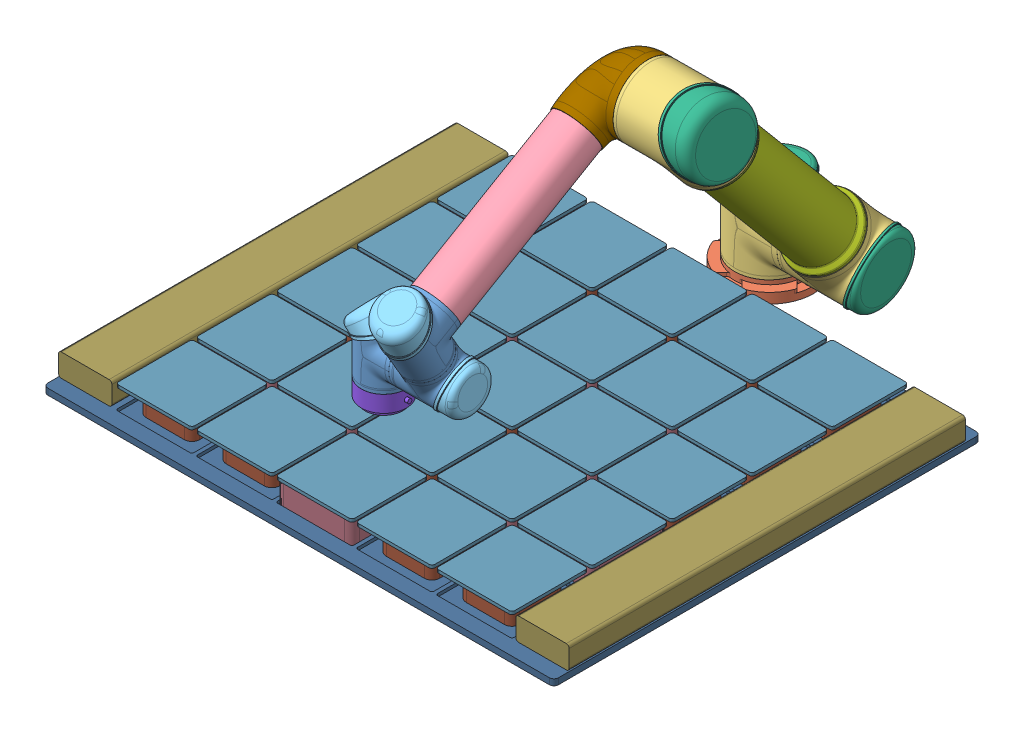
SolidWorks assembly EE206 Project, configuration Default. Lengths in mm.
Overall size (850.9 499.9 869.58).
71 component instances, 14 part files, 18 mates.
Components (placement in the parent):
- UR5-1: UR5 [Default] at origin size (344.78 499.9 760.49)
  - Size 1_House_r13_Simple-1: Size 1_House_r13_Simple [Default] at (17.3569 137.7558 566.8462) x (-0.000585 0.866025 0.500001) z (-0.003317 0.499996 -0.866021) size (83 87.5 79.44)
  - Size 1_House_r13_Simple-2: Size 1_House_r13_Simple [Default] at (-75.6425 137.5544 567.0862) x (0.999994 0.002165 -0.002581) z (0.002581 0.000003 0.999997) size (83 87.5 79.44)
  - Size 3_Round base_r02_Simple-1: Size 3_Round base_r02_Simple [Default] at (0 3 0) x (0 -1 0) z (0 0 -1) size (24 154.92 154.92)
  - Size 3_House_r11_Simple-1: Size 3_House_r11_Simple [Default] at (135.7 414.7689 273.1847) x (-0.999994 -0.002165 0.002581) z (-0.003369 0.642784 -0.76604) size (129.79 128.5 124.27)
  - Size 1 r¬r_r01_Simple-1: Size 1 r¬r_r01_Simple [Default] at (16.6562 315.7154 444.6107) x (-0.999994 -0.002165 0.002581) z (0.003317 -0.499996 0.866021) size (75 75 272.93)
  - Size 1_Joint lid_r07_Simple-1: Size 1_Joint lid_r07_Simple [Default] at (17.3025 218.2961 613.3463) x (-0.003317 0.499996 -0.866021) z (0.999994 0.002165 -0.002581) size (77.51 51.3 77.52)
  - Size 3_Joint lid_r06_Simple-1: Size 3_Joint lid_r06_Simple [Default] at (135.7003 89.2 0) x (-1 0 0) z (0 -0.642788 0.766044) size (62.7 119 119.01)
  - Size 1_House_r13_Simple-3: Size 1_House_r13_Simple [Default] at (17.3025 218.2961 613.3463) x (-0.003317 0.499996 -0.866021) z (0.999994 0.002165 -0.002581) size (83 87.5 79.44)
  - Size 3_House_r11_Simple-2: Size 3_House_r11_Simple [Default] at (135.7 89.2 0) x (-1 0 0) z (0 -0.642788 0.766044) size (129.79 128.5 124.27)
  - Size 3_Over arm_r01_Simpel-1: Size 3_Over arm_r01_Simpel [Default] at (135.7 251.9844 136.5924) x (0 -0.766044 -0.642788) z (-0.756553 0.42034 -0.500941) size (284 114.3 114.3)
  - Size 3_House_r11_Simple-3: Size 3_House_r11_Simple [Default] at (0 89.2 0) x (0 -1 0) z (0 0 -1) size (129.79 128.5 124.27)
  - Size 1_Joint lid_r07_Simple-2: Size 1_Joint lid_r07_Simple [Default] at (-59.9925 144.481 567.0458) x (-0.674003 -0.738727 0.001741) z (-0.002581 -0.000003 -0.999997) size (77.51 51.3 77.52)
  - Size 3_Joint lid_r06_Simple-2: Size 3_Joint lid_r06_Simple [Default] at (135.0062 415.9165 274.1507) x (-0.999994 -0.002165 0.002581) z (-0.003369 0.642784 -0.76604) size (62.7 119 119.01)
  - Size 1_Tool flange_r03_Simple-1: Size 1_Tool flange_r03_Simple [Default] at (-75.5397 90.0545 567.0861) x (0.002165 -0.999998 -0.000003) z (0.002581 0.000003 0.999997) size (34.5 80.5 75)
  - Size 1_Joint lid_r07_Simple-3: Size 1_Joint lid_r07_Simple [Default] at (17.3569 137.7558 566.8462) x (-0.000585 0.866025 0.500001) z (-0.003317 0.499996 -0.866021) size (77.51 51.3 77.52)
  - Size 3 to Size 1_Angle_r02_Simple-1: Size 3 to Size 1_Angle_r02_Simple [Default] at (16.0007 414.5097 273.4936) x (-0.003317 0.499996 -0.866021) z (-0.000585 0.866025 0.500001) size (132.01 97.09 116.02)
  - Size 3_Joint lid_r06_Simple-3: Size 3_Joint lid_r06_Simple [Default] at (-1.5 88.5062 0) x (0 -1 0) z (0 0 -1) size (62.7 119 119.01)
- Grid Frame-2: Grid Frame [Default] at (0 5.08 429.1) x (0 0 1) z (-1 0 0) size (711.2 10.16 850.9)
- Block Foam-1: Block Foam [Default] at (266.7 5.08 162.4) x (0 0 1) z (-1 0 0) size (88.9 38.1 88.9)
- End Block-1: End Block [Default] at (-381 10.16 429.1) x (0 0 1) z (-1 0 0) size (660.4 38.1 88.9)
- Block Wood-1: Block Wood [Default] at (-266.7 5.08 162.4) x (0 0 1) z (-1 0 0) size (127 38.1 127)
- Block Foam-2: Block Foam [Default] at (266.7 5.08 295.75) x (0 0 1) z (-1 0 0) size (88.9 38.1 88.9)
- Block Foam-3: Block Foam [Default] at (266.7 5.08 429.1) x (0 0 1) z (-1 0 0) size (88.9 38.1 88.9)
- Block Foam-5: Block Foam [Default] at (266.7 5.08 695.8) x (0 0 1) z (-1 0 0) size (88.9 38.1 88.9)
- Block Foam-6: Block Foam [Default] at (133.35 5.08 162.4) x (0 0 1) z (-1 0 0) size (88.9 38.1 88.9)
- Block Foam-10: Block Foam [Default] at (133.35 5.08 695.8) x (0 0 1) z (-1 0 0) size (88.9 38.1 88.9)
- Block Foam-11: Block Foam [Default] at (0 5.08 162.4) x (0 0 1) z (-1 0 0) size (88.9 38.1 88.9)
- Block Foam-13: Block Foam [Default] at (0 5.08 429.1) x (0 0 1) z (-1 0 0) size (88.9 38.1 88.9)
- Block Foam-14: Block Foam [Default] at (0 5.08 562.45) x (0 0 1) z (-1 0 0) size (88.9 38.1 88.9)
- Block Foam-16: Block Foam [Default] at (-133.35 5.08 162.4) x (0 0 1) z (-1 0 0) size (88.9 38.1 88.9)
- Block Foam-18: Block Foam [Default] at (-133.35 5.08 429.1) x (0 0 1) z (-1 0 0) size (88.9 38.1 88.9)
- Block Foam-20: Block Foam [Default] at (-133.35 5.08 695.8) x (0 0 1) z (-1 0 0) size (88.9 38.1 88.9)
- Block Foam-23: Block Foam [Default] at (-266.7 5.08 429.1) x (0 0 1) z (-1 0 0) size (88.9 38.1 88.9)
- Block Foam-25: Block Foam [Default] at (-266.7 5.08 695.8) x (0 0 1) z (-1 0 0) size (88.9 38.1 88.9)
- Block Wood-2: Block Wood [Default] at (-266.7 5.08 295.75) x (0 0 1) z (-1 0 0) size (127 38.1 127)
- Block Wood-3: Block Wood [Default] at (-266.7 5.08 562.45) x (0 0 1) z (-1 0 0) size (127 38.1 127)
- Block Wood-4: Block Wood [Default] at (-133.35 5.08 295.75) x (0 0 1) z (-1 0 0) size (127 38.1 127)
- Block Wood-5: Block Wood [Default] at (-133.35 5.08 562.45) x (0 0 1) z (-1 0 0) size (127 38.1 127)
- Block Wood-6: Block Wood [Default] at (0 5.08 295.75) x (0 0 1) z (-1 0 0) size (127 38.1 127)
- Block Wood-7: Block Wood [Default] at (0 5.08 695.8) x (0 0 1) z (-1 0 0) size (127 38.1 127)
- Block Wood-8: Block Wood [Default] at (133.35 5.08 295.75) x (0 0 1) z (-1 0 0) size (127 38.1 127)
- Block Wood-9: Block Wood [Default] at (133.35 5.08 429.1) x (0 0 1) z (-1 0 0) size (127 38.1 127)
- Block Wood-10: Block Wood [Default] at (133.35 5.08 562.45) x (0 0 1) z (-1 0 0) size (127 38.1 127)
- Block Wood-11: Block Wood [Default] at (266.7 5.08 562.45) x (0 0 1) z (-1 0 0) size (127 38.1 127)
- Tile-1: Tile [Default] at (266.7 43.18 162.4) x (0 0 1) z (-1 0 0) size (127 5.08 127)
- Tile-2: Tile [Default] at (266.7 43.18 295.75) x (0 0 1) z (-1 0 0) size (127 5.08 127)
- Tile-3: Tile [Default] at (266.7 43.18 429.1) x (0 0 1) z (-1 0 0) size (127 5.08 127)
- Tile-4: Tile [Default] at (266.7 43.18 562.45) x (0 0 1) z (-1 0 0) size (127 5.08 127)
- Tile-5: Tile [Default] at (266.7 43.18 695.8) x (0 0 1) z (-1 0 0) size (127 5.08 127)
- Tile-6: Tile [Default] at (133.35 43.18 162.4) x (0 0 1) z (-1 0 0) size (127 5.08 127)
- Tile-7: Tile [Default] at (133.35 43.18 295.75) x (0 0 1) z (-1 0 0) size (127 5.08 127)
- Tile-8: Tile [Default] at (133.35 43.18 429.1) x (0 0 1) z (-1 0 0) size (127 5.08 127)
- Tile-9: Tile [Default] at (133.35 43.18 562.45) x (0 0 1) z (-1 0 0) size (127 5.08 127)
- Tile-10: Tile [Default] at (133.35 43.18 695.8) x (0 0 1) z (-1 0 0) size (127 5.08 127)
- Tile-11: Tile [Default] at (0 43.18 162.4) x (0 0 1) z (-1 0 0) size (127 5.08 127)
- Tile-12: Tile [Default] at (0 43.18 295.75) x (0 0 1) z (-1 0 0) size (127 5.08 127)
- Tile-13: Tile [Default] at (0 43.18 429.1) x (0 0 1) z (-1 0 0) size (127 5.08 127)
- Tile-14: Tile [Default] at (0 43.18 562.45) x (0 0 1) z (-1 0 0) size (127 5.08 127)
- Tile-15: Tile [Default] at (0 43.18 695.8) x (0 0 1) z (-1 0 0) size (127 5.08 127)
- Tile-16: Tile [Default] at (-133.35 43.18 162.4) x (0 0 1) z (-1 0 0) size (127 5.08 127)
- Tile-17: Tile [Default] at (-133.35 43.18 295.75) x (0 0 1) z (-1 0 0) size (127 5.08 127)
- Tile-18: Tile [Default] at (-133.35 43.18 429.1) x (0 0 1) z (-1 0 0) size (127 5.08 127)
- Tile-19: Tile [Default] at (-133.35 43.18 562.45) x (0 0 1) z (-1 0 0) size (127 5.08 127)
- Tile-20: Tile [Default] at (-133.35 43.18 695.8) x (0 0 1) z (-1 0 0) size (127 5.08 127)
- Tile-21: Tile [Default] at (-266.7 43.18 162.4) x (0 0 1) z (-1 0 0) size (127 5.08 127)
- Tile-22: Tile [Default] at (-266.7 43.18 295.75) x (0 0 1) z (-1 0 0) size (127 5.08 127)
- Tile-23: Tile [Default] at (-266.7 43.18 429.1) x (0 0 1) z (-1 0 0) size (127 5.08 127)
- Tile-24: Tile [Default] at (-266.7 43.18 562.45) x (0 0 1) z (-1 0 0) size (127 5.08 127)
- Tile-25: Tile [Default] at (-266.7 43.18 695.8) x (0 0 1) z (-1 0 0) size (127 5.08 127)
- End Block-3: End Block [Default] at (381 10.16 429.1) x (0 0 1) z (-1 0 0) size (660.4 38.1 88.9)
Mates (geometry in assembly coordinates):
- Coincident29: coordinate: point of UR5-1; point of assembly
- Coincident28: coincident anti-aligned: plane of UR5-1/Size 3_Round base_r02_Simple-1 through (-73.5 0 0) normal (0 -1 0); plane of assembly through (0 0 0) normal (0 1 0)
- Coincident30: coincident anti-aligned: plane of Grid Frame-2 through (0 0 429.1) normal (0 -1 0); plane of assembly through (0 0 0) normal (0 1 0)
- Perpendicular1: perpendicular: plane of Grid Frame-2 through (0 5.08 429.1) normal (0 0 1); plane of assembly through (0 0 0) normal (1 0 0)
- Coincident33: coincident anti-aligned: plane of Grid Frame-2 through (0 5.08 429.1) normal (0 1 0); plane of Block Foam-1 through (298.45 5.08 194.15) normal (0 -1 0)
- Width1: width aligned: plane of Block Foam-1 through (234.95 43.18 206.85) normal (0 0 1); plane of Block Foam-1 through (234.95 43.18 117.95) normal (0 0 -1); plane of Grid Frame-2 through (0 10.16 98.9) normal (0 0 1); plane of Grid Frame-2 through (0 10.16 225.9) normal (0 0 -1)
- Width2: width anti-aligned: plane of Block Foam-1 through (311.15 43.18 130.65) normal (1 0 0); plane of Block Foam-1 through (222.25 43.18 130.65) normal (-1 0 0); plane of Grid Frame-2 through (330.2 10.16 429.1) normal (-1 0 0); plane of Grid Frame-2 through (203.2 10.16 429.1) normal (1 0 0)
- Coincident34: coincident anti-aligned: plane of Grid Frame-2 through (0 5.08 429.1) normal (0 1 0); plane of Block Wood-1 through (-215.9 5.08 213.2) normal (0 -1 0)
- Width5: width anti-aligned: plane of Block Wood-1 through (-317.5 43.18 98.9) normal (0 0 -1); plane of Block Wood-1 through (-317.5 43.18 225.9) normal (0 0 1); plane of Grid Frame-2 through (0 10.16 98.9) normal (0 0 1); plane of Grid Frame-2 through (0 10.16 225.9) normal (0 0 -1)
- Width6: width anti-aligned: plane of Block Wood-1 through (-203.2 43.18 111.6) normal (1 0 0); plane of Block Wood-1 through (-330.2 43.18 111.6) normal (-1 0 0); plane of Grid Frame-2 through (-203.2 10.16 429.1) normal (-1 0 0); plane of Grid Frame-2 through (-330.2 10.16 429.1) normal (1 0 0)
- Coincident35: coincident anti-aligned: plane of Block Foam-1 through (298.45 43.18 194.15) normal (0 1 0); plane of Tile-1 through (266.7 43.18 162.4) normal (0 -1 0)
- Width7: width aligned: plane of Tile-1 through (203.2 48.26 98.9) normal (0 0 -1); plane of Tile-1 through (203.2 48.26 225.9) normal (0 0 1); plane of Grid Frame-2 through (0 10.16 225.9) normal (0 0 -1); plane of Grid Frame-2 through (0 10.16 98.9) normal (0 0 1)
- Width8: width anti-aligned: plane of Tile-1 through (203.2 48.26 225.9) normal (-1 0 0); plane of Tile-1 through (330.2 48.26 225.9) normal (1 0 0); plane of Grid Frame-2 through (203.2 10.16 429.1) normal (1 0 0); plane of Grid Frame-2 through (330.2 10.16 429.1) normal (-1 0 0)
- Coincident36: coincident anti-aligned: plane of Grid Frame-2 through (0 10.16 429.1) normal (0 1 0); plane of End Block-1 through (-381 10.16 429.1) normal (0 -1 0)
- Coincident37: coincident anti-aligned: plane of Grid Frame-2 through (0 5.08 429.1) normal (-1 0 0); plane of assembly through (0 0 0) normal (1 0 0)
- Tangent1: tangent anti-aligned: plane of Grid Frame-2 through (0 10.16 73.5) normal (0 0 -1); cylinder of UR5-1/Size 3_Round base_r02_Simple-1 through (0 0 0) axis (0 1 0) radius 73.5
- Symmetric1: symmetric aligned: plane of End Block-1 through (-425.45 48.26 759.3) normal (0 0 1); plane of End Block-1 through (-425.45 48.26 98.9) normal (0 0 -1); plane of Grid Frame-2 through (0 5.08 429.1) normal (0 0 1)
- Coincident39: coincident aligned: plane of Grid Frame-2 through (-425.45 10.16 429.1) normal (-1 0 0); plane of End Block-1 through (-425.45 48.26 98.9) normal (-1 0 0)
